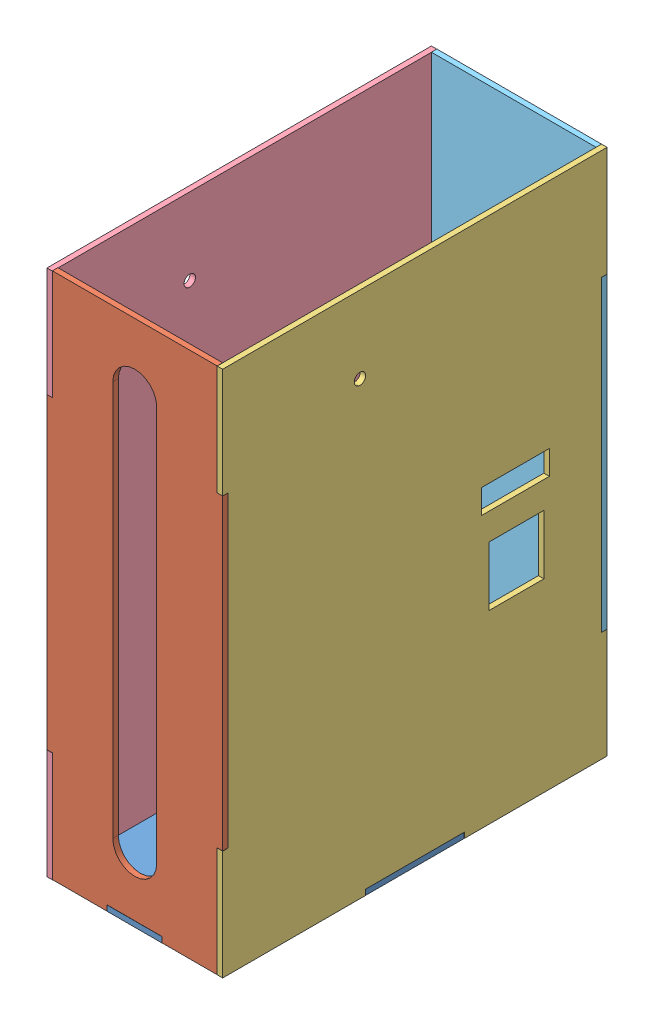
SolidWorks assembly Assem1, configuration Default. Lengths in mm.
Overall size (203.4 609.95 444.68).
5 component instances, 5 part files, 4 mates.
Components (placement in the parent):
- bottompanel-1: bottompanel [Default] at (498.4461 216.0983 182.1118) x (1 0 0) z (0 -1 0) size (203.2 444.5 6.35)
- frontpanel-1: frontpanel [Default] at (1073.4427 884.6723 578.1643) x (1 0 0) z (0 0 -1) size (203.2 609.6 6.35)
- rightpanel-1: rightpanel [Default] at (257.7632 209.8387 127.4786) x (0 0 -1) z (1 0 0) size (444.5 609.6 6.35)
- leftpanel-1: leftpanel [Default] at (60.7708 209.489 127.3034) x (0 0 -1) z (0 -1 0) size (444.5 6.35 609.6)
- backpanel-2: backpanel [Default] at (48.1474 209.7322 140.1004) x (-1 0 0) z (0 0 -1) size (203.2 609.6 6.35)
Mates (geometry in assembly coordinates):
- Perpendicular1: perpendicular: plane of bottompanel-1 through (194.0838 -415.1502 578.2704) normal (0 0 1); plane of frontpanel-1 through (130.5659 216.1137 1389.3595) normal (0 -1 0)
- Perpendicular2: perpendicular: plane of bottompanel-1 through (263.9338 209.7483 413.1704) normal (1 0 0); plane of rightpanel-1 through (1207.2072 216.1887 413.2286) normal (0 -1 0)
- Perpendicular3: perpendicular: plane of bottompanel-1 through (60.7338 -404.5752 413.1704) normal (-1 0 0); plane of leftpanel-1 through (1010.2147 215.839 298.7534) normal (0 -1 0)
- Perpendicular4: perpendicular: plane of bottompanel-1 through (130.5838 -430.2554 133.7704) normal (0 0 -1); plane of backpanel-2 through (193.9066 216.0742 -680.1514) normal (0 -1 0)
